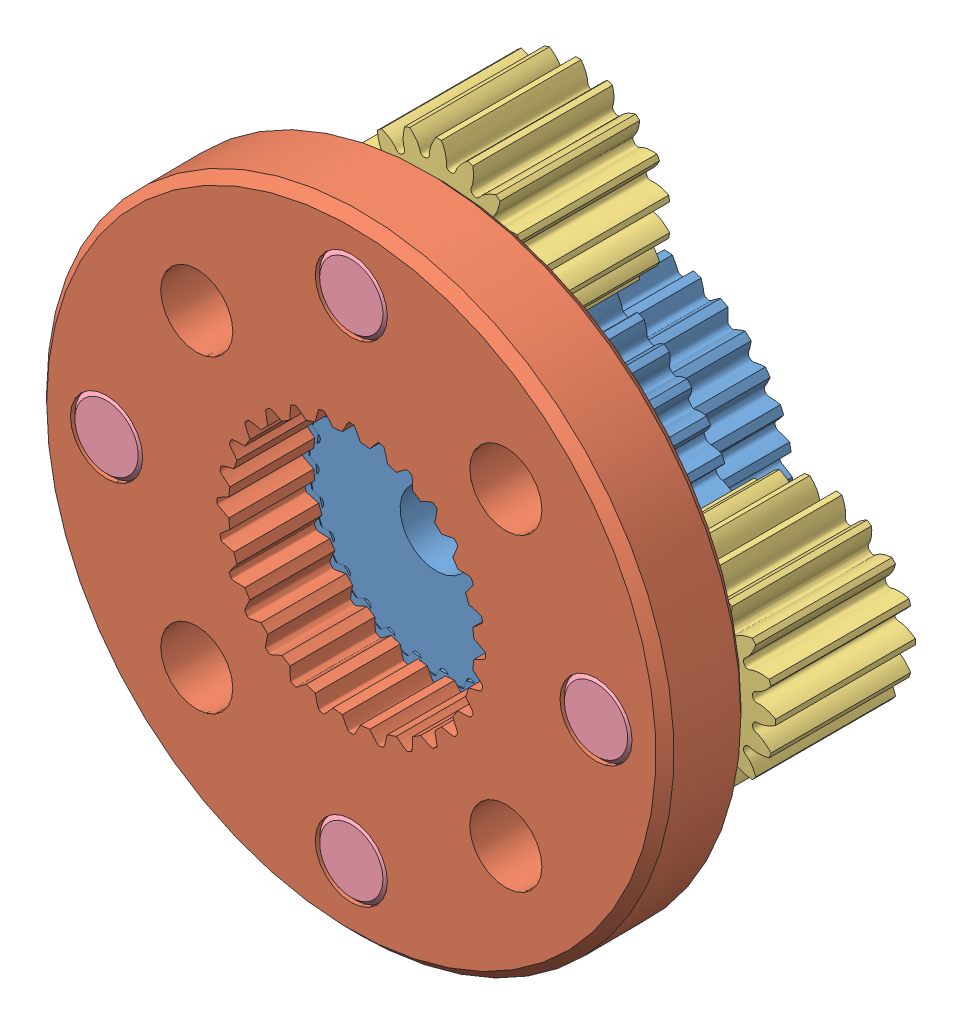
SolidWorks assembly 217-2817-STEP, configuration Default. Lengths in mm.
Overall size (37.47 37.47 17.4).
10 component instances, 4 part files, 18 mates.
Components (placement in the parent):
- 217-2724-001 Rev1_Sun_Driver01-1: 217-2724-001 Rev1_Sun_Driver01 [Default] at (0 0 -6.375) x (0.984808 0.173648 0) z (0 0 1) size (18.94 18.95 12.7)
- 217-2724-002 Rev1-1: 217-2724-002 Rev1 [Default] at (0 0 -2.35) x (0 1 0) z (0 0 1) size (34.7 34.7 4.7)
- 217-2724-003 Rev1_Planet_Revolving_Follower01-1: 217-2724-003 Rev1_Planet_Revolving_Follower01 [Default] at (0 13.5382 -8.7) x (-1 0 0) z (0 0 1) size (10.3 10.39 8.06)
- 217-2625-010 Rev1-1: 217-2625-010 Rev1 [Default] at (0 13.5382 -6) x (0.999987 -0.005082 0) z (0 0 1) size (4 4 12)
- 217-2625-010 Rev1-2: 217-2625-010 Rev1 [Default] at (13.5382 0 -6) x (-0.005082 -0.999987 0) z (0 0 1) size (4 4 12)
- 217-2625-010 Rev1-3: 217-2625-010 Rev1 [Default] at (0 -13.5382 -6) x (-0.999987 0.005082 0) z (0 0 1) size (4 4 12)
- 217-2625-010 Rev1-4: 217-2625-010 Rev1 [Default] at (-13.5382 0 -6) x (0.005082 0.999987 0) z (0 0 1) size (4 4 12)
- 217-2724-003 Rev1_Planet_Revolving_Follower01-2: 217-2724-003 Rev1_Planet_Revolving_Follower01 [Default] at (13.5382 0 -8.7) x (0 1 0) z (0 0 1) size (10.3 10.39 8.06)
- 217-2724-003 Rev1_Planet_Revolving_Follower01-3: 217-2724-003 Rev1_Planet_Revolving_Follower01 [Default] at (0 -13.5382 -8.7) size (10.3 10.39 8.06)
- 217-2724-003 Rev1_Planet_Revolving_Follower01-4: 217-2724-003 Rev1_Planet_Revolving_Follower01 [Default] at (-13.5382 0 -8.7) x (0 -1 0) z (0 0 1) size (10.3 10.39 8.06)
Mates (geometry in assembly coordinates):
- Concentric1: concentric anti-aligned: cylinder of 217-2724-002 Rev1-1 through (0 13.5382 -4.7) axis (0 0 1) radius 1.9962; cylinder of 217-2625-010 Rev1-1 through (0 13.5382 0) axis (0 0 -1) radius 2
- Coincident1: coincident aligned: plane of 217-2724-002 Rev1-1 through (0 0 0) normal (0 0 1); plane of 217-2625-010 Rev1-1 through (0 13.5382 0) normal (0 0 1)
- Coincident2: coincident anti-aligned: plane of 217-2724-002 Rev1-1 through (0 0 -4.7) normal (0 0 -1); plane of 217-2724-003 Rev1_Planet_Revolving_Follower01-1 through (0 13.5382 -4.7) normal (0 0 1)
- Concentric2: concentric anti-aligned: cylinder of 217-2724-003 Rev1_Planet_Revolving_Follower01-1 through (0 13.5382 -12.7) axis (0 0 1) radius 2.0152; cylinder of 217-2625-010 Rev1-1 through (0 13.5382 0) axis (0 0 -1) radius 2
- Coincident3: coincident anti-aligned: plane of 217-2724-002 Rev1-1 through (0 0 0) normal (0 0 1); circle of 217-2625-010 Rev1-3
- Coincident4: coincident anti-aligned: plane of 217-2724-002 Rev1-1 through (0 0 -4.7) normal (0 0 -1); plane of 217-2724-003 Rev1_Planet_Revolving_Follower01-3 through (0 -13.5382 -4.7) normal (0 0 1)
- Concentric3: concentric anti-aligned: cylinder of 217-2724-002 Rev1-1 through (0 -13.5382 -4.7) axis (0 0 1) radius 1.9962; cylinder of 217-2625-010 Rev1-3 through (0 -13.5382 0) axis (0 0 -1) radius 2
- Concentric4: concentric anti-aligned: cylinder of 217-2625-010 Rev1-3 through (0 -13.5382 0) axis (0 0 -1) radius 2; cylinder of 217-2724-003 Rev1_Planet_Revolving_Follower01-3 through (0 -13.5382 -12.7) axis (0 0 1) radius 2.0152
- Coincident5: coincident aligned: plane of 217-2724-002 Rev1-1 through (0 0 0) normal (0 0 1); plane of 217-2625-010 Rev1-2 through (13.5382 0 0) normal (0 0 1)
- Concentric5: concentric anti-aligned: cylinder of 217-2724-002 Rev1-1 through (13.5382 0 -4.7) axis (0 0 1) radius 1.9962; cylinder of 217-2625-010 Rev1-2 through (13.5382 0 0) axis (0 0 -1) radius 2
- Coincident6: coincident anti-aligned: plane of 217-2724-002 Rev1-1 through (0 0 -4.7) normal (0 0 -1); plane of 217-2724-003 Rev1_Planet_Revolving_Follower01-2 through (13.5382 0 -4.7) normal (0 0 1)
- Concentric6: concentric anti-aligned: cylinder of 217-2625-010 Rev1-2 through (13.5382 0 0) axis (0 0 -1) radius 2; cylinder of 217-2724-003 Rev1_Planet_Revolving_Follower01-2 through (13.5382 0 -12.7) axis (0 0 1) radius 2.0152
- Coincident7: coincident aligned: plane of 217-2724-002 Rev1-1 through (0 0 0) normal (0 0 1); plane of 217-2625-010 Rev1-4 through (-13.5382 0 0) normal (0 0 1)
- Concentric7: concentric anti-aligned: cylinder of 217-2724-002 Rev1-1 through (-13.5382 0 -4.7) axis (0 0 1) radius 1.9962; cylinder of 217-2625-010 Rev1-4 through (-13.5382 0 0) axis (0 0 -1) radius 2
- Coincident8: coincident anti-aligned: plane of 217-2724-002 Rev1-1 through (0 0 -4.7) normal (0 0 -1); plane of 217-2724-003 Rev1_Planet_Revolving_Follower01-4 through (-13.5382 0 -4.7) normal (0 0 1)
- Concentric8: concentric anti-aligned: cylinder of 217-2625-010 Rev1-4 through (-13.5382 0 0) axis (0 0 -1) radius 2; cylinder of 217-2724-003 Rev1_Planet_Revolving_Follower01-4 through (-13.5382 0 -12.7) axis (0 0 1) radius 2.0152
- Concentric9: concentric: cylinder of 217-2724-001 Rev1_Sun_Driver01-1 through (0 0 -17.4) axis (0 0 1) radius 2; cylinder of 217-2724-002 Rev1-1 through (0 0 0) axis (0 0 -1) radius 17.35
- Coincident9: coincident anti-aligned: plane of 217-2724-001 Rev1_Sun_Driver01-1 through (-6.4182 1.0494 -4.7) normal (0 0 1); plane of 217-2724-002 Rev1-1 through (0 0 -4.7) normal (0 0 -1)
